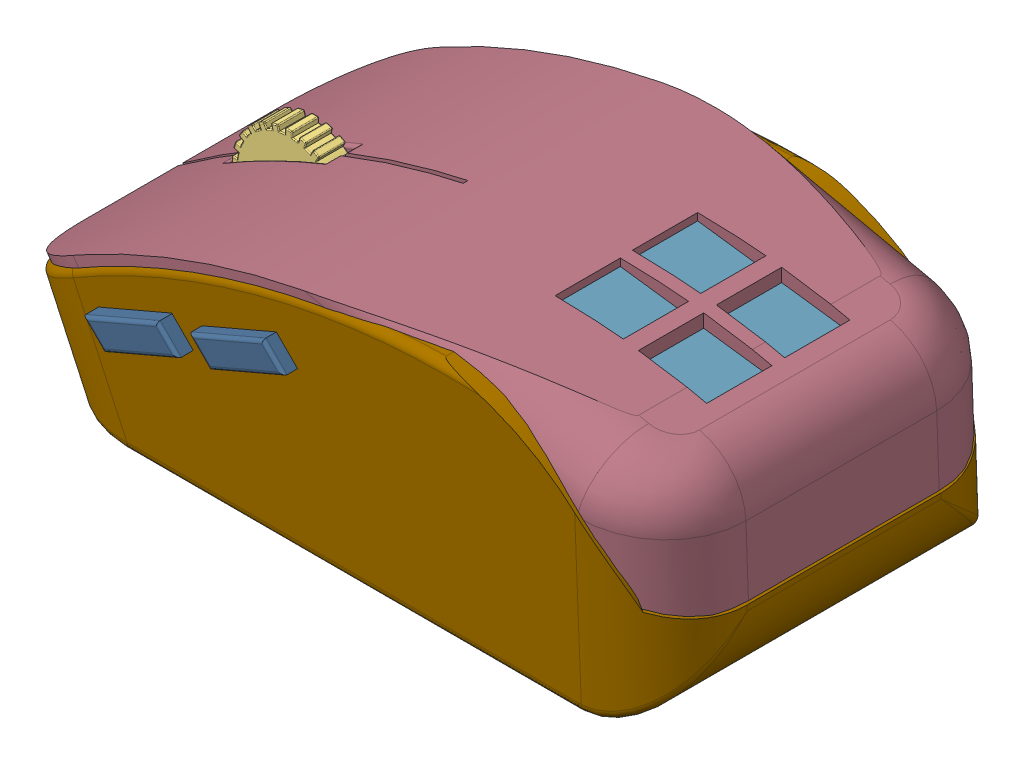
SolidWorks assembly Improved Computer Mouse, configuration Default. Lengths in mm.
Overall size (100.52 36.55 61.44).
22 component instances, 14 part files, 0 mates.
Components (placement in the parent):
- Bottom Cover-1: Bottom Cover [Default] at (27.3346 57.3723 115.2019) x (1 0 0) z (0 -0.008727 -0.999962) size (43.84 1.27 24.37)
- LED Diode-1: LED Diode [Default] at (56.156 61.583 79.4106) x (0.906308 -0.422618 0) z (0 0 1) size (4.51 17.27 4.51)
- Scroll Wheel-1: Scroll Wheel [Default] at (21.9296 75.9132 92.53) size (17.2 17.17 12.19)
- On Button-1: On Button [Default] at (80.4151 56.9013 94.4898) size (8.22 5.33 8.22)
- Mirror-1: Mirror [Default] at (61.3697 54.9758 76.5973) x (-0.008503 0.001963 0.999962) z (-0.974333 0.224942 -0.008727) size (5.84 5.52 7.15)
- Glidey Pad-1: Glidey Pad [Default] at (18.3947 56.1068 92.4502) x (0.999848 0 0.017452) z (-0.000152 -0.999962 0.008725) size (13.63 46.98 0.82)
- Glidey Pad-2: Glidey Pad [Default] at (81.9887 55.217 92.7992) x (-0.99981 0.008725 0.017452) z (0.008878 0.999923 0.008725) size (13.63 46.98 0.82)
- Battery-1: Battery [Default] at (75.9228 60.3645 125.2957) size (42.83 8.56 8.56)
- Spring-1: Spring [Default] at (71.1704 59.1571 109.0655) x (0.008727 0.999962 0) z (0 0 1) size (4.81 1.9 5.09)
- Improved Mouse Body-1: Improved Mouse Body [Default] at (53.164 55.5362 67.1132) size (100.21 35.52 58.44)
- Side Button-2: Side Button [Default] at (39.3817 47.5364 120.4593) size (16.46 10.05 4.57)
- Side Button-3: Side Button [Default] at (55.0794 53.0044 120.249) size (16.46 10.05 4.57)
- LED Diode-2: LED Diode [Default] at (73.7889 86.281 89.3223) x (-0.953717 0.300706 0) z (0 0 1) size (4.51 17.27 4.51)
- Blue Diode-1: Blue Diode [Default] at (85.3132 83.8692 88.8881) x (-0.965926 0.258819 0) z (0 0 1) size (4.51 17.27 4.51)
- Green Diode-1: Green Diode [Default] at (79.4733 85.0067 89.1041) x (-0.95882 0.284015 0) z (0 0 1) size (4.51 17.27 4.51)
- Improved Top Cover-1: Improved Top Cover [Default] at (52.1891 57.5229 67.2196) size (100.33 23.49 61.1)
- Shine-through material-1: Shine-through material [Default] at (120.2499 81.2082 108.3054) x (0.991445 -0.130526 0) z (0 0 1) size (34.41 2.54 34.17)
- LED Diode-3: LED Diode [Default] at (32.2051 82.3352 94.8686) x (-0.945519 -0.325568 0) z (0 0 1) size (4.51 17.27 4.51)
- Green Diode-2: Green Diode [Default] at (37.5326 84.6921 94.6503) x (-0.939693 -0.34202 0) z (0 0 1) size (4.51 17.27 4.51)
- Blue Diode-2: Blue Diode [Default] at (85.3132 83.8692 99.3015) x (-0.965926 0.258819 0) z (0 0 1) size (4.51 17.27 4.51)
- LED Diode-5: LED Diode [Default] at (73.7889 86.281 99.7358) x (-0.953717 0.300706 0) z (0 0 1) size (4.51 17.27 4.51)
- Green Diode-4: Green Diode [Default] at (79.4733 85.0067 99.5175) x (-0.95882 0.284015 0) z (0 0 1) size (4.51 17.27 4.51)
